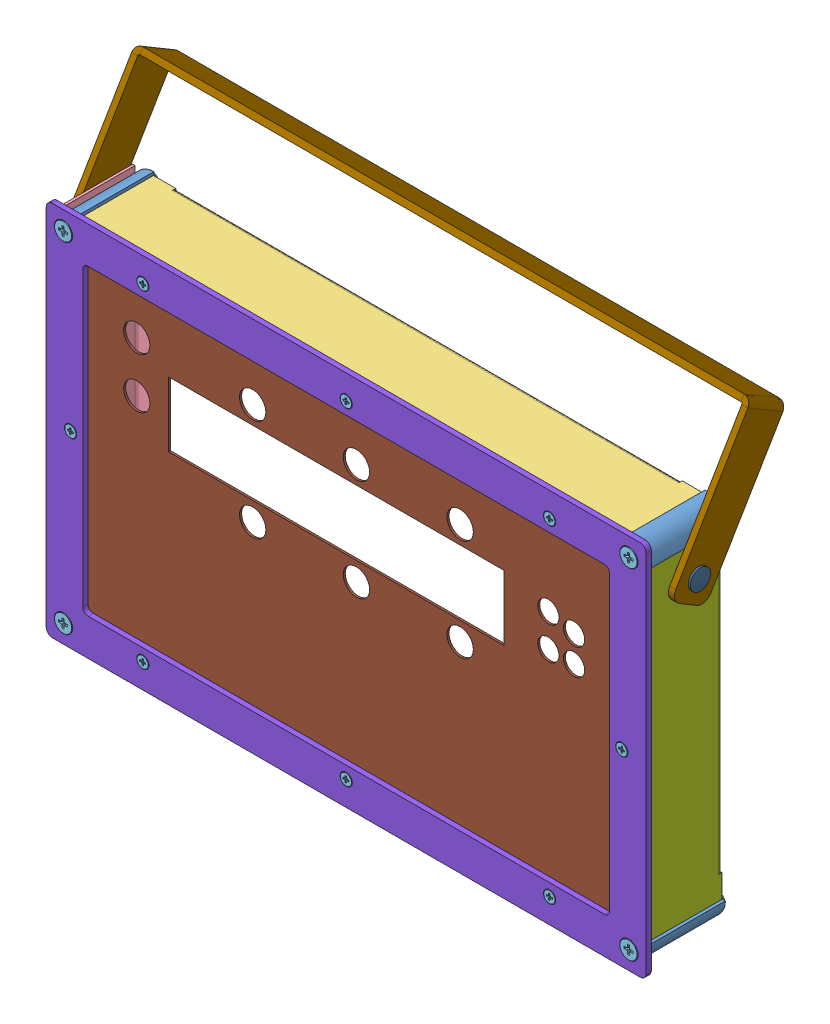
SolidWorks assembly BTEC 112 001 - Montagem teclado, configuration Valor predeterminado. Lengths in mm.
Overall size (306 226.05 65.29).
41 component instances, 13 part files, 73 mates.
Components (placement in the parent):
- BTEC 112 102 - Teclado base-1: BTEC 112 102 - Teclado base [Default] at (4.9222 -13.5946 -1) size (295 185 2) (hidden)
- BTEC 112 112 - Teclado perfil-1: BTEC 112 112 - Teclado perfil [Default] at (-130.3278 -93.3446 20) x (0 1 0) z (0 0 -1) size (20.5 20.5 38)
- BTEC 112 112 - Teclado perfil-2: BTEC 112 112 - Teclado perfil [Default] at (-130.3278 66.1554 20) x (1 0 0) z (0 0 -1) size (20.5 20.5 38)
- BTEC 112 112 - Teclado perfil-3: BTEC 112 112 - Teclado perfil [Default] at (140.1722 66.1554 20) x (0 -1 0) z (0 0 -1) size (20.5 20.5 38)
- BTEC 112 112 - Teclado perfil-4: BTEC 112 112 - Teclado perfil [Default] at (140.1722 -93.3446 20) x (0 1 0) z (0 0 1) size (20.5 20.5 38)
- BTEC 112 107 - Teclado lateral inferior-1: BTEC 112 107 - Teclado lateral inferior [Valor predeterminado] at (4.9222 -100.8946 20.2) x (-1 0 0) z (0 0 -1) size (275 10.2 38.4)
- BTEC 112 108 - Teclado lateral superior-1: BTEC 112 108 - Teclado lateral superior [Valor predeterminado] at (4.9222 73.7054 20.2) x (1 0 0) z (0 0 -1) size (275 10.2 38.4)
- BTEC 112 106 - Teclado lateral esquerda-1: BTEC 112 106 - Teclado lateral esquerda [Valor predeterminado] at (-137.8778 -13.5946 20.2) x (0 1 0) z (0 0 -1) size (180 11.2 38.4)
- countersunk flat head cross recess screw_iso-1: countersunk flat head cross recess screw_iso [ISO 7046-1 - M3 x 12 - Z --- 12N] at (-76.5778 -81.0946 -1.15) x (0 0 1) z (-1 0 0) size (12 5.5 5.5)
- countersunk flat head cross recess screw_iso-2: countersunk flat head cross recess screw_iso [ISO 7046-1 - M3 x 12 - Z --- 12N] at (-89.5778 -81.0946 -1.15) x (0 0 1) z (-1 0 0) size (12 5.5 5.5)
- countersunk flat head cross recess screw_iso-3: countersunk flat head cross recess screw_iso [ISO 7046-1 - M3 x 12 - Z --- 12N] at (-95.0778 -94.0946 42.05) x (0 0 -1) z (1 0 0) size (12 5.5 5.5)
- countersunk flat head cross recess screw_iso-4: countersunk flat head cross recess screw_iso [ISO 7046-1 - M3 x 12 - Z --- 12N] at (4.9222 -94.0946 42.05) x (0 0 -1) z (1 0 0) size (12 5.5 5.5)
- countersunk flat head cross recess screw_iso-5: countersunk flat head cross recess screw_iso [ISO 7046-1 - M3 x 12 - Z --- 12N] at (104.9222 -94.0946 42.05) x (0 0 -1) z (1 0 0) size (12 5.5 5.5)
- countersunk flat head cross recess screw_iso-6: countersunk flat head cross recess screw_iso [ISO 7046-1 - M3 x 12 - Z --- 12N] at (140.4222 -13.5946 42.05) x (0 0 -1) z (1 0 0) size (12 5.5 5.5)
- countersunk flat head cross recess screw_iso-7: countersunk flat head cross recess screw_iso [ISO 7046-1 - M3 x 12 - Z --- 12N] at (-130.5778 -13.5946 42.05) x (0 0 -1) z (1 0 0) size (12 5.5 5.5)
- countersunk flat head cross recess screw_iso-8: countersunk flat head cross recess screw_iso [ISO 7046-1 - M3 x 12 - Z --- 12N] at (104.9222 66.9054 42.05) x (0 0 -1) z (1 0 0) size (12 5.5 5.5)
- countersunk flat head cross recess screw_iso-9: countersunk flat head cross recess screw_iso [ISO 7046-1 - M3 x 12 - Z --- 12N] at (4.9222 66.9054 42.05) x (0 0 -1) z (1 0 0) size (12 5.5 5.5)
- countersunk flat head cross recess screw_iso-10: countersunk flat head cross recess screw_iso [ISO 7046-1 - M3 x 12 - Z --- 12N] at (-95.0778 66.9054 42.05) x (0 0 -1) z (1 0 0) size (12 5.5 5.5)
- countersunk flat head cross recess screw_iso-11: countersunk flat head cross recess screw_iso [ISO 7046-1 - M4 x 12 - Z --- 12N] at (-134.0778 69.9054 42.12) x (0 0 -1) z (1 0 0) size (12 8.4 8.4)
- countersunk flat head cross recess screw_iso-12: countersunk flat head cross recess screw_iso [ISO 7046-1 - M4 x 12 - Z --- 12N] at (-134.0778 -97.0946 42.12) x (0 0 -1) z (1 0 0) size (12 8.4 8.4)
- countersunk flat head cross recess screw_iso-13: countersunk flat head cross recess screw_iso [ISO 7046-1 - M4 x 12 - Z --- 12N] at (-134.0778 69.9054 -1.2) x (0 0 1) z (-1 0 0) size (12 8.4 8.4)
- countersunk flat head cross recess screw_iso-14: countersunk flat head cross recess screw_iso [ISO 7046-1 - M4 x 12 - Z --- 12N] at (-134.0778 -97.0946 -1.2) x (0 0 1) z (-1 0 0) size (12 8.4 8.4)
- countersunk flat head cross recess screw_iso-15: countersunk flat head cross recess screw_iso [ISO 7046-1 - M4 x 12 - Z --- 12N] at (143.9222 69.9054 42.12) x (0 0 -1) z (1 0 0) size (12 8.4 8.4)
- countersunk flat head cross recess screw_iso-16: countersunk flat head cross recess screw_iso [ISO 7046-1 - M4 x 12 - Z --- 12N] at (143.9222 -97.0946 42.12) x (0 0 -1) z (1 0 0) size (12 8.4 8.4)
- countersunk flat head cross recess screw_iso-17: countersunk flat head cross recess screw_iso [ISO 7046-1 - M4 x 12 - Z --- 12N] at (143.9222 69.9054 -1.2) x (0 0 1) z (-1 0 0) size (12 8.4 8.4)
- countersunk flat head cross recess screw_iso-18: countersunk flat head cross recess screw_iso [ISO 7046-1 - M4 x 12 - Z --- 12N] at (143.9222 -97.0946 -1.2) x (0 0 1) z (-1 0 0) size (12 8.4 8.4)
- hex nut style 1 gradeab_iso-1: hex nut style 1 gradeab_iso [Hexagon Nut ISO - 4032 - M3 - W - N] at (-95.0778 66.9054 36) x (0.923728 0.383049 0) z (0 0 -1) size (5.5 6.35 2.4)
- hex nut style 1 gradeab_iso-2: hex nut style 1 gradeab_iso [Hexagon Nut ISO - 4032 - M3 - W - N] at (-95.0778 -94.0946 36) x (0.923728 0.383049 0) z (0 0 -1) size (5.5 6.35 2.4)
- hex nut style 1 gradeab_iso-3: hex nut style 1 gradeab_iso [Hexagon Nut ISO - 4032 - M3 - W - N] at (4.9222 66.9054 36) x (0.923728 0.383049 0) z (0 0 -1) size (5.5 6.35 2.4)
- hex nut style 1 gradeab_iso-4: hex nut style 1 gradeab_iso [Hexagon Nut ISO - 4032 - M3 - W - N] at (140.4222 -13.5946 36) x (0.923728 0.383049 0) z (0 0 -1) size (5.5 6.35 2.4)
- hex nut style 1 gradeab_iso-5: hex nut style 1 gradeab_iso [Hexagon Nut ISO - 4032 - M3 - W - N] at (104.9222 -94.0946 36) x (0.923728 0.383049 0) z (0 0 -1) size (5.5 6.35 2.4)
- hex nut style 1 gradeab_iso-6: hex nut style 1 gradeab_iso [Hexagon Nut ISO - 4032 - M3 - W - N] at (4.9222 -94.0946 36) x (0.923728 0.383049 0) z (0 0 -1) size (5.5 6.35 2.4)
- hex nut style 1 gradeab_iso-7: hex nut style 1 gradeab_iso [Hexagon Nut ISO - 4032 - M3 - W - N] at (-130.5778 -13.5946 36) x (0.923728 0.383049 0) z (0 0 -1) size (5.5 6.35 2.4)
- hex nut style 1 gradeab_iso-8: hex nut style 1 gradeab_iso [Hexagon Nut ISO - 4032 - M3 - W - N] at (104.9222 66.9054 36) x (0.923728 0.383049 0) z (0 0 -1) size (5.5 6.35 2.4)
- BTEC 112 105 - Teclado lateral direita-2: BTEC 112 105 - Teclado lateral direita [Valor predeterminado] at (147.7222 -13.5946 20.2) x (0 -1 0) z (0 0 -1) size (165 10.2 38.4)
- BTEC 112 109 - Teclado moldura-1: BTEC 112 109 - Teclado moldura [Default] at (4.9222 -13.5946 40.65) size (295 185 2.5)
- BTEC 112 101 - Teclado alça-1: BTEC 112 101 - Teclado alça [Default] at (4.9222 80.0364 6.135) x (1 0 0) z (0 0.511456 0.85931) size (303 83 20)
- BTEC 112 113 - Teclado pino-1: BTEC 112 113 - Teclado pino [Default] at (-137.5778 56.4054 20.2) x (1 0 0) z (0 -0.648895 0.760878) size (15.5 10 10)
- BTEC 112 113 - Teclado pino-2: BTEC 112 113 - Teclado pino [Default] at (147.4222 56.4054 20.2) x (-1 0 0) z (0 -0.924225 -0.381849) size (15.5 10 10)
- BTEC 112 103 - Teclado display-1: BTEC 112 103 - Teclado display [Default] at (4.9222 -13.5946 38.4) size (276 168 1)
- BTEC 112 104 - Teclado fixador de cabo-1: BTEC 112 104 - Teclado fixador de cabo [Default] at (-83.0778 -81.0946 4.5) size (20 15 7)
Mates (geometry in assembly coordinates):
- Coincidente1: coincident anti-aligned: plane of BTEC 112 102 - Teclado base-1 through (150.9222 -104.5946 1) normal (0 0 1); plane of BTEC 112 112 - Teclado perfil-1 through (-130.5778 -93.5946 1) normal (0 0 -1)
- Paralelo1: parallel aligned: plane of BTEC 112 102 - Teclado base-1 through (-142.5778 77.4054 1) normal (-1 0 0); plane of BTEC 112 112 - Teclado perfil-1 through (-137.8778 -83.0946 39) normal (-1 0 0)
- Coincidente4: coincident anti-aligned: plane of BTEC 112 102 - Teclado base-1 through (150.9222 -104.5946 1) normal (0 0 1); plane of BTEC 112 112 - Teclado perfil-2 through (-130.5778 66.4054 1) normal (0 0 -1)
- Paralelo2: parallel aligned: plane of BTEC 112 102 - Teclado base-1 through (-142.5778 77.4054 1) normal (-1 0 0); plane of BTEC 112 112 - Teclado perfil-2 through (-137.8778 55.9054 39) normal (-1 0 0)
- Coincidente8: coincident anti-aligned: plane of BTEC 112 102 - Teclado base-1 through (150.9222 -104.5946 1) normal (0 0 1); plane of BTEC 112 112 - Teclado perfil-4 through (140.4222 -93.5946 1) normal (0 0 -1)
- Paralelo3: parallel aligned: plane of BTEC 112 102 - Teclado base-1 through (152.4222 77.4054 1) normal (1 0 0); plane of BTEC 112 112 - Teclado perfil-4 through (147.7222 -83.0946 1) normal (1 0 0)
- Coincidente11: coincident anti-aligned: plane of BTEC 112 102 - Teclado base-1 through (150.9222 -104.5946 1) normal (0 0 1); plane of BTEC 112 112 - Teclado perfil-3 through (140.4222 66.4054 1) normal (0 0 -1)
- Paralelo4: parallel aligned: plane of BTEC 112 102 - Teclado base-1 through (152.4222 77.4054 1) normal (1 0 0); plane of BTEC 112 112 - Teclado perfil-3 through (147.7222 55.9054 39) normal (1 0 0)
- Largura2: width anti-aligned: plane of BTEC 112 112 - Teclado perfil-4 through (142.9222 -100.8946 1) normal (-1 0 0); plane of BTEC 112 112 - Teclado perfil-1 through (-133.0778 -100.8946 39) normal (1 0 0); plane of BTEC 112 107 - Teclado lateral inferior-1 through (142.4222 -100.158 39.4) normal (1 0 0); plane of BTEC 112 107 - Teclado lateral inferior-1 through (-132.5778 -100.158 1) normal (-1 0 0)
- Coincidente14: coincident anti-aligned: plane of BTEC 112 102 - Teclado base-1 through (150.9222 -104.5946 1) normal (0 0 1); plane of BTEC 112 107 - Teclado lateral inferior-1 through (-132.5778 -91.8946 1) normal (0 0 -1)
- Largura3: width anti-aligned: plane of BTEC 112 112 - Teclado perfil-1 through (-120.0778 -100.8946 39) normal (0 -1 0); plane of BTEC 112 112 - Teclado perfil-1 through (-133.0778 -102.0946 39) normal (0 1 0); plane of BTEC 112 107 - Teclado lateral inferior-1 through (-132.5778 -100.8946 2.2) normal (0 1 0); plane of BTEC 112 107 - Teclado lateral inferior-1 through (-132.5778 -102.0946 2.2) normal (0 -1 0)
- Coincidente16: coincident anti-aligned: plane of BTEC 112 102 - Teclado base-1 through (150.9222 -104.5946 1) normal (0 0 1); plane of BTEC 112 108 - Teclado lateral superior-1 through (142.4222 64.7054 1) normal (0 0 -1)
- Largura4: width aligned: plane of BTEC 112 112 - Teclado perfil-2 through (-120.0778 73.7054 39) normal (0 1 0); plane of BTEC 112 112 - Teclado perfil-2 through (-133.0778 74.9054 39) normal (0 -1 0); plane of BTEC 112 108 - Teclado lateral superior-1 through (142.4222 74.9054 2.2) normal (0 1 0); plane of BTEC 112 108 - Teclado lateral superior-1 through (142.4222 73.7054 2.2) normal (0 -1 0)
- Largura5: width anti-aligned: plane of BTEC 112 108 - Teclado lateral superior-1 through (142.4222 72.9688 1) normal (1 0 0); plane of BTEC 112 108 - Teclado lateral superior-1 through (-132.5778 72.9688 39.4) normal (-1 0 0); plane of BTEC 112 112 - Teclado perfil-3 through (142.9222 73.7054 39) normal (-1 0 0); plane of BTEC 112 112 - Teclado perfil-2 through (-133.0778 73.7054 39) normal (1 0 0)
- Coincidente17: coincident anti-aligned: plane of BTEC 112 102 - Teclado base-1 through (150.9222 -104.5946 1) normal (0 0 1); plane of BTEC 112 105 - Teclado lateral direita-2 through (138.7222 -96.0946 1) normal (0 0 -1)
- Coincidente18: coincident anti-aligned: plane of BTEC 112 102 - Teclado base-1 through (150.9222 -104.5946 1) normal (0 0 1); plane of BTEC 112 106 - Teclado lateral esquerda-1 through (-127.8778 76.4054 1) normal (0 0 -1)
- Largura6: width anti-aligned: plane of BTEC 112 106 - Teclado lateral esquerda-1 through (-139.0778 76.4054 2.2) normal (-1 0 0); plane of BTEC 112 106 - Teclado lateral esquerda-1 through (-137.8778 76.4054 2.2) normal (1 0 0); plane of BTEC 112 112 - Teclado perfil-2 through (-139.0778 68.9054 39) normal (1 0 0); plane of BTEC 112 112 - Teclado perfil-2 through (-137.8778 55.9054 39) normal (-1 0 0)
- Largura7: width anti-aligned: plane of BTEC 112 105 - Teclado lateral direita-2 through (146.9856 -96.0946 1) normal (0 -1 0); plane of BTEC 112 105 - Teclado lateral direita-2 through (146.9856 68.9054 39.4) normal (0 1 0); plane of BTEC 112 112 - Teclado perfil-4 through (147.7222 -96.0946 1) normal (0 1 0); plane of BTEC 112 112 - Teclado perfil-3 through (147.7222 68.9054 39) normal (0 -1 0)
- Largura8: width anti-aligned: plane of BTEC 112 112 - Teclado perfil-3 through (147.7222 55.9054 39) normal (1 0 0); plane of BTEC 112 112 - Teclado perfil-3 through (148.9222 68.9054 39) normal (-1 0 0); plane of BTEC 112 105 - Teclado lateral direita-2 through (147.7222 -96.0946 2.2) normal (-1 0 0); plane of BTEC 112 105 - Teclado lateral direita-2 through (148.9222 -96.0946 2.2) normal (1 0 0)
- Largura9: width anti-aligned: plane of BTEC 112 112 - Teclado perfil-2 through (-137.8778 68.9054 39) normal (0 -1 0); plane of BTEC 112 112 - Teclado perfil-1 through (-137.8778 -96.0946 39) normal (0 1 0); plane of BTEC 112 106 - Teclado lateral esquerda-1 through (-137.1412 76.4054 1) normal (0 1 0); plane of BTEC 112 106 - Teclado lateral esquerda-1 through (-137.1412 -103.5946 39.4) normal (0 -1 0)
- Concêntrico10: concentric anti-aligned: circle of BTEC 112 112 - Teclado perfil-3; circle of BTEC 112 109 - Teclado moldura-1
- Concêntrico11: concentric aligned: circle of BTEC 112 112 - Teclado perfil-4; circle of BTEC 112 109 - Teclado moldura-1
- Coincidente21: coincident anti-aligned: plane of BTEC 112 108 - Teclado lateral superior-1 through (142.4222 73.7054 39.4) normal (0 0 1); plane of BTEC 112 109 - Teclado moldura-1 through (149.4222 -103.0946 39.4) normal (0 0 -1)
- Concêntrico12: concentric anti-aligned: cylinder of BTEC 112 106 - Teclado lateral esquerda-1 through (-127.8778 56.4054 20.2) axis (-1 0 0) radius 4; cylinder of BTEC 112 101 - Teclado alça-1 through (-146.5778 56.4054 20.2) axis (1 0 0) radius 4
- Largura10: width anti-aligned: plane of BTEC 112 101 - Teclado alça-1 through (-143.5778 48.6303 36.4649) normal (1 0 0); plane of BTEC 112 101 - Teclado alça-1 through (153.4222 117.3751 -4.4515) normal (-1 0 0); plane of BTEC 112 106 - Teclado lateral esquerda-1 through (-139.0778 76.4054 2.2) normal (-1 0 0); plane of BTEC 112 105 - Teclado lateral direita-2 through (148.9222 -96.0946 2.2) normal (1 0 0)
- Concêntrico13: concentric anti-aligned: cylinder of BTEC 112 101 - Teclado alça-1 through (-146.5778 56.4054 20.2) axis (1 0 0) radius 4; cylinder of BTEC 112 113 - Teclado pino-1 through (-171.1969 56.4054 20.2) axis (-1 0 0) radius 4
- Coincidente22: coincident anti-aligned: plane of BTEC 112 101 - Teclado alça-1 through (-146.5778 48.6303 36.4649) normal (-1 0 0); plane of BTEC 112 113 - Teclado pino-1 through (-146.5778 60.2098 23.4445) normal (1 0 0)
- Concêntrico14: concentric aligned: cylinder of BTEC 112 101 - Teclado alça-1 through (-146.5778 56.4054 20.2) axis (1 0 0) radius 4; cylinder of BTEC 112 113 - Teclado pino-2 through (181.0413 56.4054 20.2) axis (1 0 0) radius 4
- Coincidente23: coincident anti-aligned: plane of BTEC 112 101 - Teclado alça-1 through (156.4222 117.3751 -4.4515) normal (1 0 0); plane of BTEC 112 113 - Teclado pino-2 through (156.4222 58.3147 15.5789) normal (-1 0 0)
- Concêntrico15: concentric aligned: cylinder of BTEC 112 109 - Teclado moldura-1 through (104.9222 66.9054 41.9) axis (0 0 1) radius 1.7; cylinder of BTEC 112 103 - Teclado display-1 through (104.9222 66.9054 38.4) axis (0 0 1) radius 1.6
- Concêntrico16: concentric aligned: cylinder of BTEC 112 109 - Teclado moldura-1 through (4.9222 66.9054 41.9) axis (0 0 1) radius 1.7; cylinder of BTEC 112 103 - Teclado display-1 through (4.9222 66.9054 38.4) axis (0 0 1) radius 1.6
- Coincidente24: coincident anti-aligned: plane of BTEC 112 109 - Teclado moldura-1 through (149.4222 -103.0946 39.4) normal (0 0 -1); plane of BTEC 112 103 - Teclado display-1 through (134.9222 -79.5946 39.4) normal (0 0 1)
- Coincidente25: coincident anti-aligned: plane of BTEC 112 102 - Teclado base-1 through (150.9222 -104.5946 1) normal (0 0 1); plane of BTEC 112 104 - Teclado fixador de cabo-1 through (-93.0778 -88.5946 1) normal (0 0 -1)
- Concêntrico17: concentric aligned: cylinder of BTEC 112 102 - Teclado base-1 through (-89.5778 -81.0946 1) axis (0 0 1) radius 1.25; cylinder of BTEC 112 104 - Teclado fixador de cabo-1 through (-89.5778 -81.0946 1) axis (0 0 1) radius 1.2
- Concêntrico18: concentric aligned: cylinder of BTEC 112 102 - Teclado base-1 through (-76.5778 -81.0946 1) axis (0 0 1) radius 1.25; cylinder of BTEC 112 104 - Teclado fixador de cabo-1 through (-76.5778 -81.0946 1) axis (0 0 1) radius 1.2
- Coincidente26: coincident aligned: cone of BTEC 112 102 - Teclado base-1 through (-89.5778 -81.0946 0.75) axis (0 0 1); cone of countersunk flat head cross recess screw_iso-2 through (-89.5778 -81.0946 -0.75) axis (0 0 1)
- Coincidente27: coincident aligned: cone of BTEC 112 102 - Teclado base-1 through (-76.5778 -81.0946 0.75) axis (0 0 1); cone of countersunk flat head cross recess screw_iso-1 through (-76.5778 -81.0946 -0.75) axis (0 0 1)
- Coincidente28: coincident aligned: cone of BTEC 112 109 - Teclado moldura-1 through (-95.0778 -94.0946 41.9) axis (0 0 -1); cone of countersunk flat head cross recess screw_iso-3 through (-95.0778 -94.0946 41.65) axis (0 0 -1)
- Coincidente29: coincident aligned: cone of BTEC 112 109 - Teclado moldura-1 through (4.9222 -94.0946 41.9) axis (0 0 -1); cone of countersunk flat head cross recess screw_iso-4 through (4.9222 -94.0946 41.65) axis (0 0 -1)
- Coincidente30: coincident aligned: cone of BTEC 112 109 - Teclado moldura-1 through (104.9222 -94.0946 41.9) axis (0 0 -1); cone of countersunk flat head cross recess screw_iso-5 through (104.9222 -94.0946 41.65) axis (0 0 -1)
- Coincidente31: coincident aligned: cone of BTEC 112 109 - Teclado moldura-1 through (140.4222 -13.5946 41.9) axis (0 0 -1); cone of countersunk flat head cross recess screw_iso-6 through (140.4222 -13.5946 41.65) axis (0 0 -1)
- Coincidente32: coincident aligned: cone of BTEC 112 109 - Teclado moldura-1 through (-130.5778 -13.5946 41.9) axis (0 0 -1); cone of countersunk flat head cross recess screw_iso-7 through (-130.5778 -13.5946 41.65) axis (0 0 -1)
- Coincidente33: coincident aligned: cone of BTEC 112 109 - Teclado moldura-1 through (-95.0778 66.9054 41.9) axis (0 0 -1); cone of countersunk flat head cross recess screw_iso-10 through (-95.0778 66.9054 41.65) axis (0 0 -1)
- Coincidente35: coincident aligned: cone of BTEC 112 109 - Teclado moldura-1 through (4.9222 66.9054 41.9) axis (0 0 -1); cone of countersunk flat head cross recess screw_iso-9 through (4.9222 66.9054 41.65) axis (0 0 -1)
- Coincidente36: coincident aligned: cone of BTEC 112 109 - Teclado moldura-1 through (104.9222 66.9054 41.9) axis (0 0 -1); cone of countersunk flat head cross recess screw_iso-8 through (104.9222 66.9054 41.65) axis (0 0 -1)
- Coincidente37: coincident aligned: cone of BTEC 112 109 - Teclado moldura-1 through (-134.0778 69.9054 41.9) axis (0 0 -1); cone of countersunk flat head cross recess screw_iso-11 through (-134.0778 69.9054 41.62) axis (0 0 -1)
- Coincidente38: coincident aligned: cone of BTEC 112 109 - Teclado moldura-1 through (-134.0778 -97.0946 41.9) axis (0 0 -1); cone of countersunk flat head cross recess screw_iso-12 through (-134.0778 -97.0946 41.62) axis (0 0 -1)
- Coincidente39: coincident aligned: cone of BTEC 112 102 - Teclado base-1 through (-134.0778 -97.0946 1.85) axis (0 0 1); cone of countersunk flat head cross recess screw_iso-14 through (-134.0778 -97.0946 -0.7) axis (0 0 1)
- Coincidente40: coincident aligned: cone of BTEC 112 102 - Teclado base-1 through (-134.0778 69.9054 1.85) axis (0 0 1); cone of countersunk flat head cross recess screw_iso-13 through (-134.0778 69.9054 -0.7) axis (0 0 1)
- Coincidente41: coincident aligned: cone of BTEC 112 102 - Teclado base-1 through (143.9222 69.9054 1.85) axis (0 0 1); cone of countersunk flat head cross recess screw_iso-17 through (143.9222 69.9054 -0.7) axis (0 0 1)
- Coincidente42: coincident aligned: cone of BTEC 112 102 - Teclado base-1 through (143.9222 -97.0946 1.85) axis (0 0 1); cone of countersunk flat head cross recess screw_iso-18 through (143.9222 -97.0946 -0.7) axis (0 0 1)
- Coincidente43: coincident aligned: cone of BTEC 112 109 - Teclado moldura-1 through (143.9222 -97.0946 41.9) axis (0 0 -1); cone of countersunk flat head cross recess screw_iso-16 through (143.9222 -97.0946 41.62) axis (0 0 -1)
- Coincidente44: coincident aligned: cone of BTEC 112 109 - Teclado moldura-1 through (143.9222 69.9054 41.9) axis (0 0 -1); cone of countersunk flat head cross recess screw_iso-15 through (143.9222 69.9054 41.62) axis (0 0 -1)
- Concêntrico27: concentric anti-aligned: circle of BTEC 112 102 - Teclado base-1; circle of BTEC 112 112 - Teclado perfil-2
- Concêntrico28: concentric anti-aligned: circle of BTEC 112 112 - Teclado perfil-2; circle of BTEC 112 109 - Teclado moldura-1
- Concêntrico29: concentric anti-aligned: circle of BTEC 112 102 - Teclado base-1; circle of BTEC 112 112 - Teclado perfil-1
- Concêntrico30: concentric aligned: circle of BTEC 112 102 - Teclado base-1; circle of BTEC 112 112 - Teclado perfil-4
- Concêntrico31: concentric anti-aligned: cylinder of countersunk flat head cross recess screw_iso-8 through (104.9222 66.9054 48.4) axis (0 0 1) radius 1.5; cylinder of hex nut style 1 gradeab_iso-8 through (104.9222 66.9054 38.4) axis (0 0 -1) radius 1.25
- Concêntrico32: concentric anti-aligned: cylinder of countersunk flat head cross recess screw_iso-9 through (4.9222 66.9054 48.4) axis (0 0 1) radius 1.5; cylinder of hex nut style 1 gradeab_iso-3 through (4.9222 66.9054 38.4) axis (0 0 -1) radius 1.25
- Concêntrico33: concentric anti-aligned: cylinder of countersunk flat head cross recess screw_iso-10 through (-95.0778 66.9054 48.4) axis (0 0 1) radius 1.5; cylinder of hex nut style 1 gradeab_iso-1 through (-95.0778 66.9054 38.4) axis (0 0 -1) radius 1.25
- Concêntrico34: concentric anti-aligned: cylinder of countersunk flat head cross recess screw_iso-6 through (140.4222 -13.5946 48.4) axis (0 0 1) radius 1.5; cylinder of hex nut style 1 gradeab_iso-4 through (140.4222 -13.5946 38.4) axis (0 0 -1) radius 1.25
- Concêntrico35: concentric anti-aligned: cylinder of countersunk flat head cross recess screw_iso-5 through (104.9222 -94.0946 48.4) axis (0 0 1) radius 1.5; cylinder of hex nut style 1 gradeab_iso-5 through (104.9222 -94.0946 38.4) axis (0 0 -1) radius 1.25
- Concêntrico36: concentric anti-aligned: cylinder of countersunk flat head cross recess screw_iso-4 through (4.9222 -94.0946 48.4) axis (0 0 1) radius 1.5; cylinder of hex nut style 1 gradeab_iso-6 through (4.9222 -94.0946 38.4) axis (0 0 -1) radius 1.25
- Concêntrico37: concentric anti-aligned: cylinder of countersunk flat head cross recess screw_iso-3 through (-95.0778 -94.0946 48.4) axis (0 0 1) radius 1.5; cylinder of hex nut style 1 gradeab_iso-2 through (-95.0778 -94.0946 38.4) axis (0 0 -1) radius 1.25
- Concêntrico38: concentric anti-aligned: cylinder of countersunk flat head cross recess screw_iso-7 through (-130.5778 -13.5946 48.4) axis (0 0 1) radius 1.5; cylinder of hex nut style 1 gradeab_iso-7 through (-130.5778 -13.5946 38.4) axis (0 0 -1) radius 1.25
- Coincidente45: coincident anti-aligned: plane of BTEC 112 103 - Teclado display-1 through (134.9222 -79.5946 38.4) normal (0 0 -1); plane of hex nut style 1 gradeab_iso-7 through (-135.6583 -15.7014 38.4) normal (0 0 1)
- Coincidente46: coincident anti-aligned: plane of BTEC 112 103 - Teclado display-1 through (134.9222 -79.5946 38.4) normal (0 0 -1); plane of hex nut style 1 gradeab_iso-1 through (-100.1583 64.7986 38.4) normal (0 0 1)
- Coincidente47: coincident anti-aligned: plane of BTEC 112 103 - Teclado display-1 through (134.9222 -79.5946 38.4) normal (0 0 -1); plane of hex nut style 1 gradeab_iso-3 through (-0.1583 64.7986 38.4) normal (0 0 1)
- Coincidente48: coincident anti-aligned: plane of BTEC 112 103 - Teclado display-1 through (134.9222 -79.5946 38.4) normal (0 0 -1); plane of hex nut style 1 gradeab_iso-8 through (99.8417 64.7986 38.4) normal (0 0 1)
- Coincidente49: coincident anti-aligned: plane of BTEC 112 103 - Teclado display-1 through (134.9222 -79.5946 38.4) normal (0 0 -1); plane of hex nut style 1 gradeab_iso-4 through (135.3417 -15.7014 38.4) normal (0 0 1)
- Coincidente50: coincident anti-aligned: plane of BTEC 112 103 - Teclado display-1 through (134.9222 -79.5946 38.4) normal (0 0 -1); plane of hex nut style 1 gradeab_iso-5 through (99.8417 -96.2014 38.4) normal (0 0 1)
- Coincidente51: coincident anti-aligned: plane of BTEC 112 103 - Teclado display-1 through (134.9222 -79.5946 38.4) normal (0 0 -1); plane of hex nut style 1 gradeab_iso-6 through (-0.1583 -96.2014 38.4) normal (0 0 1)
- Coincidente52: coincident anti-aligned: plane of BTEC 112 103 - Teclado display-1 through (134.9222 -79.5946 38.4) normal (0 0 -1); plane of hex nut style 1 gradeab_iso-2 through (-100.1583 -96.2014 38.4) normal (0 0 1)
